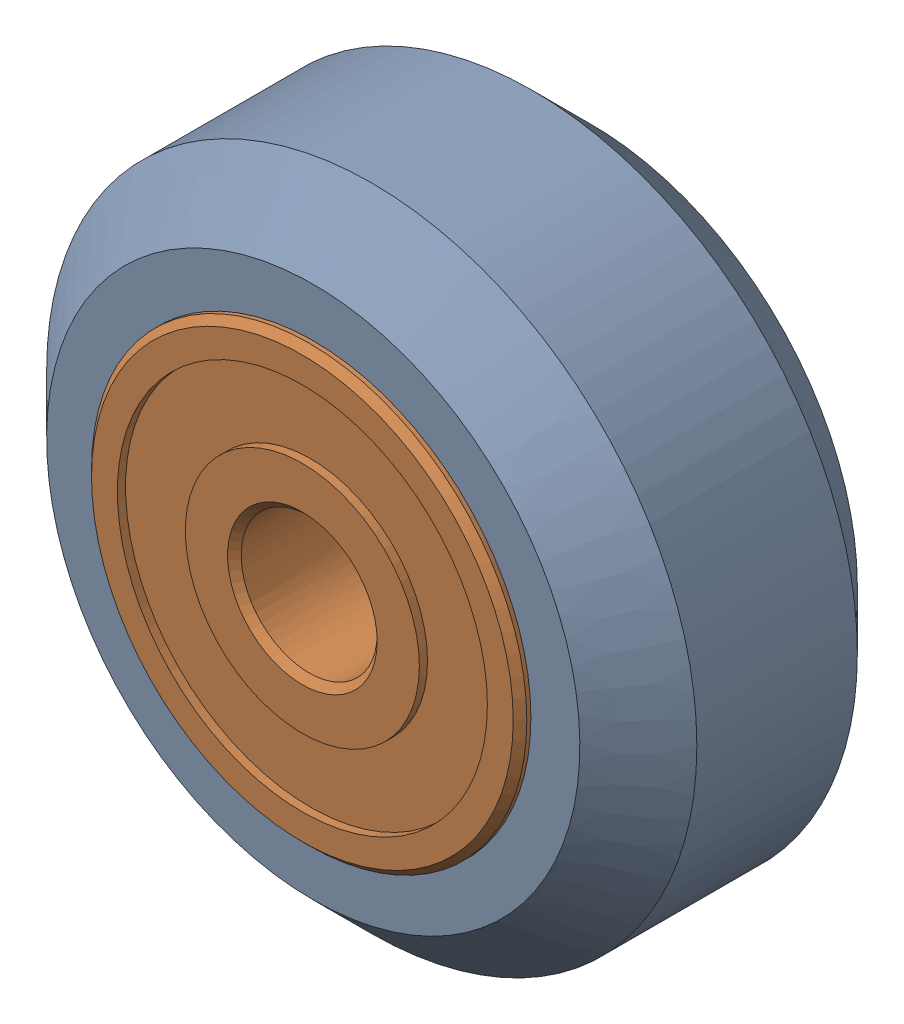
SolidWorks assembly Xtreme Solid V Wheel Assembly_2, configuration Default. Lengths in mm.
Overall size (23.9 23.9 11).
3 component instances, 2 part files, 0 mates.
Components (placement in the parent):
- Xtreme Solid V Wheel-1: Xtreme Solid V Wheel [Default] at (-154.85 -55 30) x (0 0 1) z (-1 0 0) size (10.2 23.9 23.9)
- Wheel+Kit+-+5x16x5mm+Sealed+Radial+Ball+Bearing.step.f3d-1: Wheel+Kit+-+5x16x5mm+Sealed+Radial+Ball+Bearing.step.f3d [Default] at (-154.85 -55 30) x (0 1 0) z (-1 0 0) size (16 5 16)
- Wheel+Kit+-+5x16x5mm+Sealed+Radial+Ball+Bearing.step.f3d-2: Wheel+Kit+-+5x16x5mm+Sealed+Radial+Ball+Bearing.step.f3d [Default] at (-154.85 -55 30) x (0 1 0) z (1 0 0) size (16 5 16)
